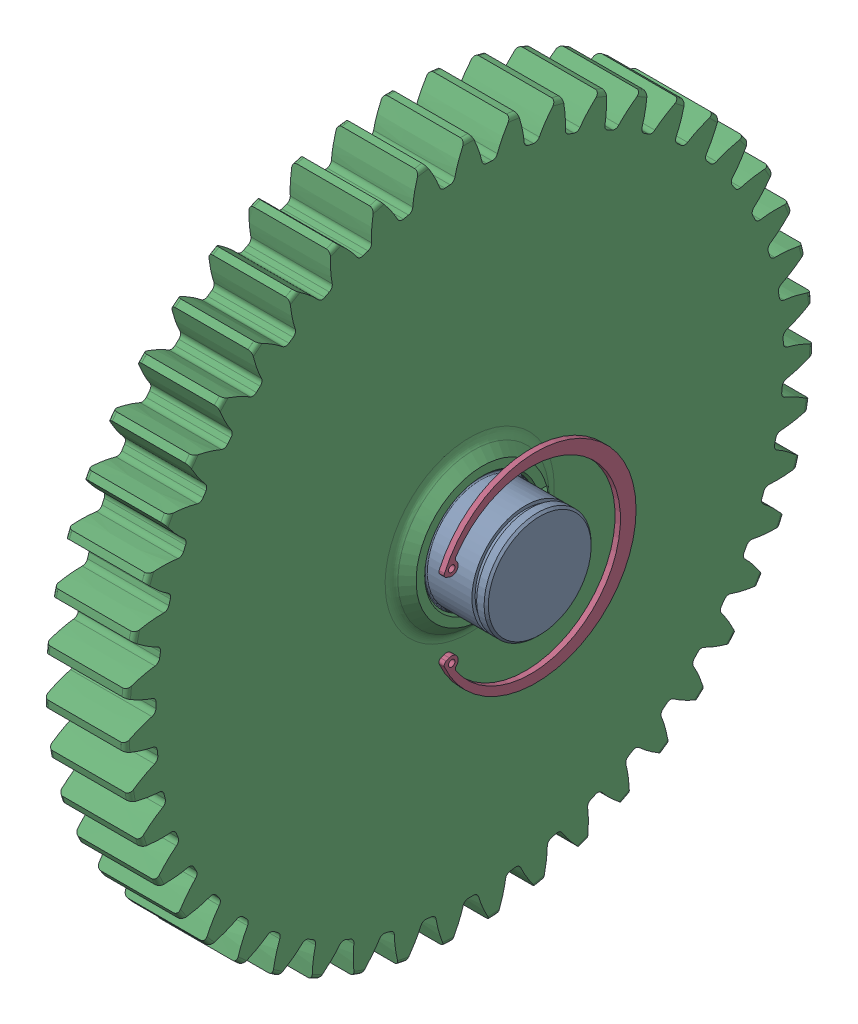
SolidWorks assembly g1_3_1_1_3, configuration 默认. Lengths in mm.
Overall size (103.5 321.87 322.01).
5 component instances, 4 part files, 0 mates.
Components (placement in the parent):
- g1_3_1_1_3-1-1: g1_3_1_1_3-1 [默认] at origin size (103.5 52 52)
- 16x10x45_gb1096-1: 16x10x45_gb1096 [默认] at (-0.5 0 25) x (1 0 0) z (0 0 -1) size (45 16 10)
- _X2_60F08F6E_X0_g1_3_1_1_3-2-1: _X2_60F08F6E_X0_g1_3_1_1_3-2 [默认] at (25 0 0) x (0 0 1) z (1 0 0) size (322.01 321.87 50.08)
- 90_gb893_1-1: 90_gb893_1 [默认] at (45.05 0 -2.4333) x (0 1 0) z (1 0 0) size (93.5 89.63 2.5)
- 90_gb893_1-2: 90_gb893_1 [默认] at (-47.55 0 -2.4333) x (0 1 0) z (1 0 0) size (93.5 89.63 2.5)
